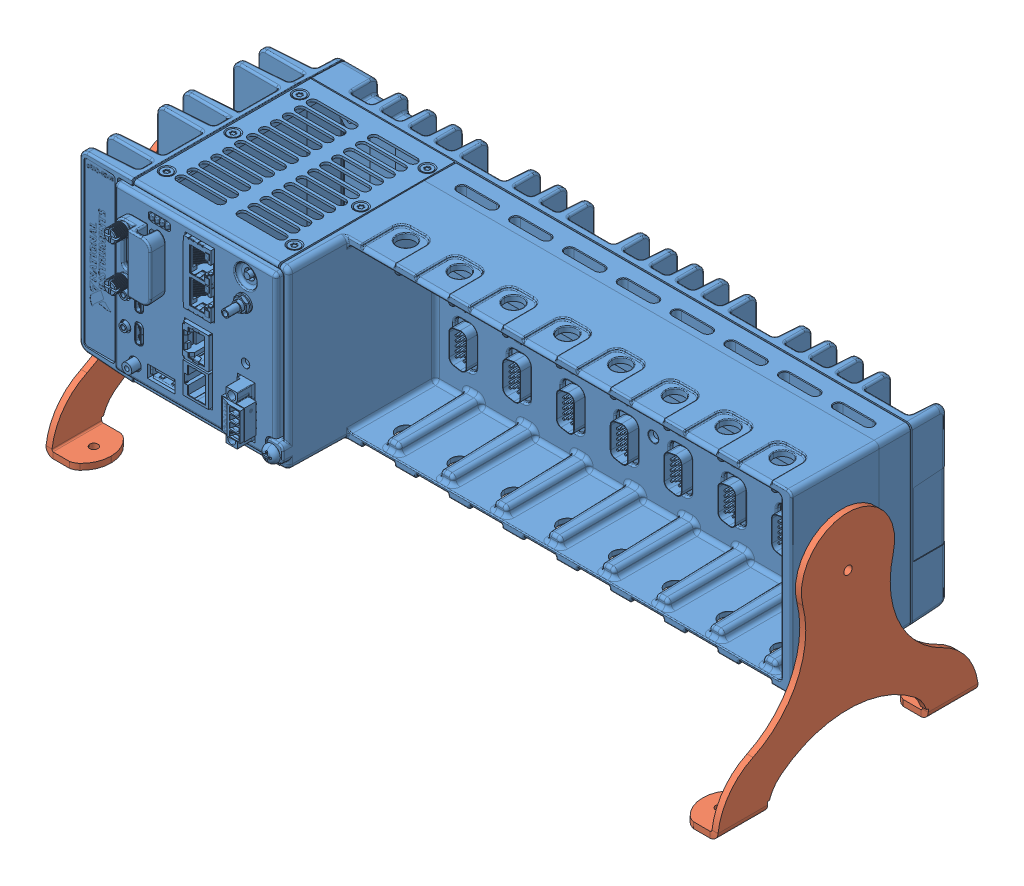
SolidWorks assembly compact, configuration Valor predeterminado. Lengths in mm.
Overall size (334.85 130.73 132.82).
3 component instances, 2 part files, 6 mates.
Components (placement in the parent):
- CRIO-1: CRIO [Valor predeterminado] at (-13.3193 107.4805 186.9873) size (328.85 91.42 122.27)
- SuporteLateral-1: SuporteLateral [Valor predeterminado] at (-130.66 22.4929 151.8888) x (0 0 1) z (-1 0 0) size (130 110 20)
- SuporteLateral-2: SuporteLateral [Valor predeterminado] at (192.1895 22.4805 281.8888) x (0 0 -1) z (1 0 0) size (130 110 20)
Mates (geometry in assembly coordinates):
- Concêntrico1: concentric: cone of assembly; cylinder of assembly; cone of CRIO-1 through (-2804.0912 107.4929 216.8888) axis (1 0 0); cylinder of SuporteLateral-1 through (-136.66 107.4929 216.8888) axis (1 0 0) radius 2.09
- Concêntrico2: concentric: cylinder of assembly; cylinder of assembly; cylinder of CRIO-1 through (183.2671 107.4805 216.8888) axis (-1 0 0) radius 1.65; cylinder of SuporteLateral-2 through (198.1895 107.4805 216.8888) axis (-1 0 0) radius 2.09
- Paralelo1: parallel: plane of assembly; plane of assembly; plane of SuporteLateral-1 through (-130.66 22.4929 151.8888) normal (0 -1 0); plane of SuporteLateral-2 through (192.1895 22.4805 281.8888) normal (0 -1 0)
- Coincidente3: coincident: line of assembly; plane of assembly; line of CRIO-1 through (195.1895 65.9639 198.3413) axis (0 1 0); plane of SuporteLateral-2 through (195.1895 22.4805 251.0056) normal (-1 0 0)
- Coincidente4: coincident: plane of assembly; plane of assembly; plane of CRIO-1 through (-133.66 63.4366 270.3103) normal (-1 0 0); plane of SuporteLateral-1 through (-133.66 22.4929 182.772) normal (1 0 0)
- Paralelo3: parallel: plane of assembly; plane of assembly; plane of CRIO-1 through (-104.1203 63.7008 268.944) normal (0 -1 0); plane of SuporteLateral-1 through (-130.66 25.4929 151.8888) normal (0 1 0)
